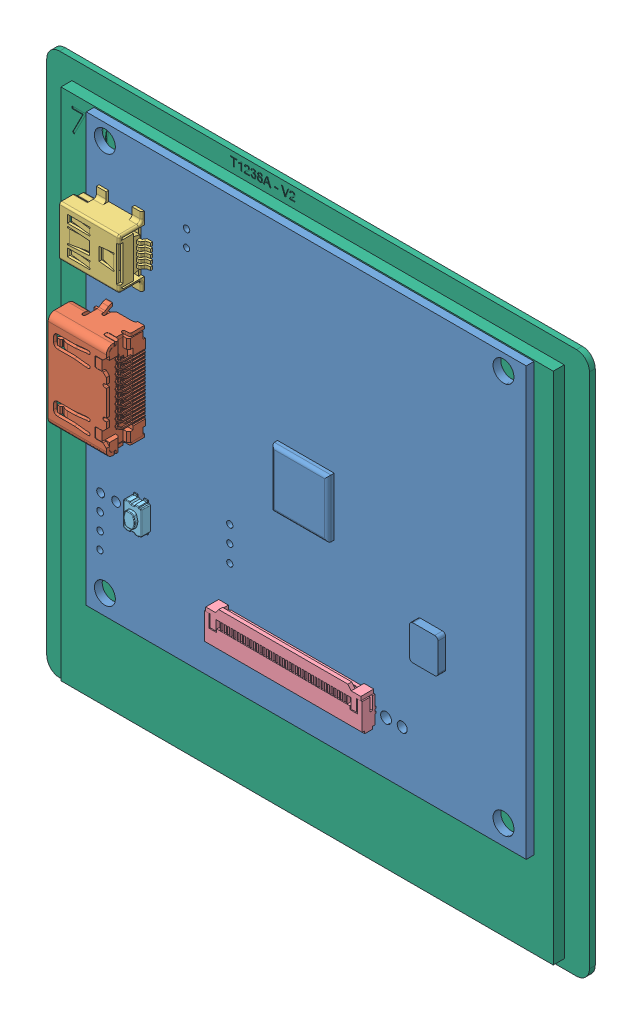
SolidWorks assembly PCB_1, configuration Défaut. Lengths in mm.
Overall size (84 84 9.7).
6 component instances, 6 part files, 12 mates.
Components (placement in the parent):
- PCBOARD-1: PCBOARD [Défaut] at (-65.2478 -245.2955 0) size (68.1 66.15 2.4)
- HDMI-1: HDMI [Défaut] at (-38.6334 3.0447 3.125) x (0 -1 0) z (-1 0 0) size (16.2 8 9.9)
- Mini USB-1: Mini USB [Default] at (-42.5505 20.538 0) size (10.5 10.7 3.9)
- Pe├ºa2-1: Pe├ºa2 [Valor predeterminado] at (-14.308 -23.1614 2.13) x (1 0 0) z (0 0 -1) size (24.4 6.45 2.13)
- KMR621NG LFS-1: KMR621NG LFS [Défaut] at (-38.4091 -14.8786 0) x (0 1 0) z (0 0 1) size (4.6 2.78 1.9)
- 720x720-1: 720x720 [Défaut] at (28.0499 -46.1494 -3.8) x (-1 0 0) z (0 0 -1) size (84 84 2.6)
Mates (geometry in assembly coordinates):
- Parallèle1: parallel anti-aligned: plane of PCBOARD-1 through (-65.2478 -245.2955 0) normal (0 0 1); plane of HDMI-1 through (-49.7834 -2.4553 0) normal (0 0 -1)
- Coïncidente2: coincident aligned: plane of PCBOARD-1 through (-46.9334 34.6679 -1.2) normal (-1 0 0); plane of HDMI-1 through (-46.9334 9.5447 4.9) normal (-1 0 0)
- Coïncidente3: coincident anti-aligned: plane of PCBOARD-1 through (-65.2478 -245.2955 0) normal (0 0 1); plane of HDMI-1 through (-49.7834 -2.4553 0) normal (0 0 -1)
- Coïncidente4: coincident anti-aligned: plane of PCBOARD-1 through (-65.2478 -245.2955 0) normal (0 0 1); plane of Mini USB-1 through (-42.5505 20.538 0) normal (0 0 -1)
- Parallèle2: parallel anti-aligned: plane of PCBOARD-1 through (-65.2478 -245.2955 0) normal (0 0 1); plane of Pe├ºa2-1 through (-14.308 -23.1614 0) normal (0 0 -1)
- Parallèle3: parallel aligned: line of PCBOARD-1 through (68.1 -46.9334 -31.4821) axis (0 1 0); line of Pe├ºa2-1 through (-26.508 -25.0114 1.73) axis (1 0 0)
- Coïncidente7: coincident anti-aligned: plane of PCBOARD-1 through (-65.2478 -245.2955 0) normal (0 0 1); plane of Pe├ºa2-1 through (-14.308 -23.1614 0) normal (0 0 -1)
- Parallèle4: parallel aligned: plane of PCBOARD-1 through (-46.9334 -31.4821 -1.2) normal (0 -1 0); plane of KMR621NG LFS-1 through (-38.6489 -16.6761 0) normal (0 -1 0)
- Coïncidente9: coincident anti-aligned: plane of PCBOARD-1 through (-65.2478 -245.2955 0) normal (0 0 1); plane of KMR621NG LFS-1 through (-38.4091 -14.864 0) normal (0 0 -1)
- Parallèle5: parallel anti-aligned: plane of PCBOARD-1 through (-65.2478 -245.2955 -1.2) normal (0 0 -1); plane of 720x720-1 through (28.0499 -46.1494 -1.2) normal (0 0 1)
- Parallèle6: parallel aligned: plane of PCBOARD-1 through (-46.9334 34.6679 -1.2) normal (0 1 0); plane of 720x720-1 through (26.0499 37.8506 -2.9) normal (0 1 0)
- Coïncidente12: coincident anti-aligned: plane of PCBOARD-1 through (-65.2478 -245.2955 -1.2) normal (0 0 -1); plane of 720x720-1 through (28.0499 -46.1494 -1.2) normal (0 0 1)
